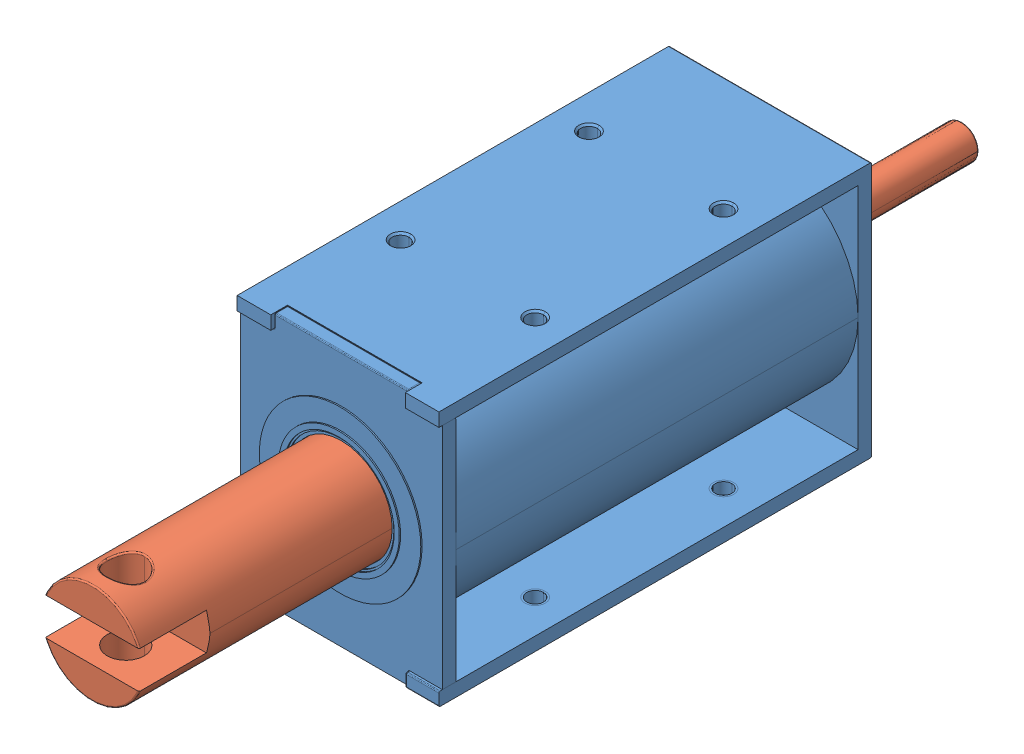
SolidWorks assembly NL3830B, configuration Default. Lengths in mm.
Overall size (30 38.01 129.3).
2 component instances, 2 part files, 4 mates.
Components (placement in the parent):
- Case-1: Case [Default] at origin size (30 38.01 64.3)
- Pin-1: Pin [Default] at (0 0 25.0538) size (15 15.07 129.3)
Mates (geometry in assembly coordinates):
- Coincident1: coordinate: point of Case-1
- Concentric1: concentric: cylinder of Case-1 through (0 0 -62.3) axis (0 0 1) radius 10; cylinder of Pin-1 through (0 0 24.5538) axis (0 0 1) radius 7.5
- Parallel1: parallel: plane of Case-1 through (15 19 0) normal (0 1 0); plane of Pin-1 through (-10.3045 -2.75 36.5538) normal (0 1 0)
- LimitDistance2: limit distance = 37.0538 mm aligned: plane of Pin-1 through (0 0 36.5538) normal (0 0 1); plane of Case-1 through (0 0 -0.5) normal (0 0 1)
